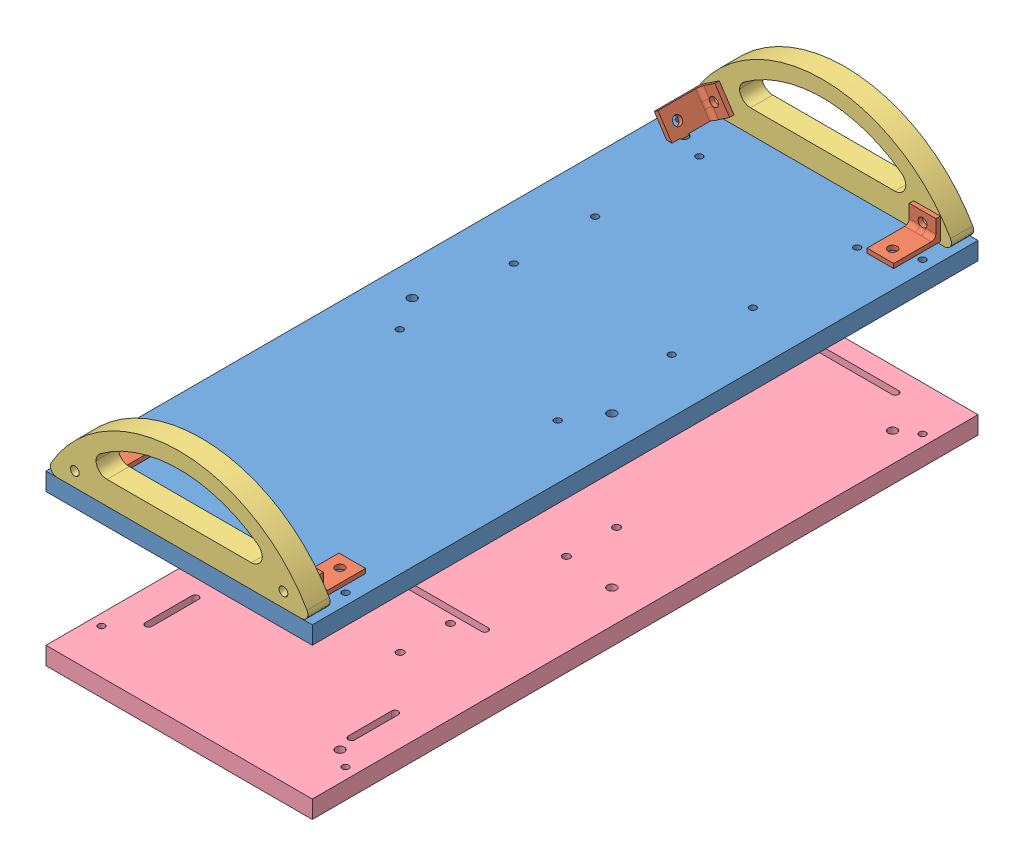
SolidWorks assembly e TRAY ASSEMBLY, configuration Default. Lengths in mm.
Overall size (150 150 300).
8 component instances, 4 part files, 16 mates.
Components (placement in the parent):
- E tray lower-1: E tray lower [Default] at (-39.2466 76 -235.5889) x (0 0 1) z (1 0 0) size (300 8 120)
- l BRACKETT-5: l BRACKETT [Default] at (-24.605 136.2584 -283.17) x (0 1 0) z (0 0 1) size (10 12 21)
- l BRACKETT-6: l BRACKETT [Default] at (-36.605 136.2584 -16.83) x (0 1 0) z (0 0 -1) size (10 12 21)
- l BRACKETT-7: l BRACKETT [Default] at (-76.5282 107.2908 -283.17) x (0.832473 0.554065 0) z (0 0 1) size (10 12 21)
- l BRACKETT-8: l BRACKETT [Default] at (-130.605 136.2584 -16.83) x (0 1 0) z (0 0 -1) size (10 12 21)
- E TRAY SUPPORT-2: E TRAY SUPPORT [Default] at (-77.605 47.3598 -300) x (-1 0 0) z (0 1 0) size (116.08 10 37.84)
- E TRAY SUPPORT-3: E TRAY SUPPORT [Default] at (-77.605 47.3598 -10) x (-1 0 0) z (0 1 0) size (116.08 10 37.84)
- E tray upper-1: E tray upper [Default] at (-52.9013 8 -233.0125) x (0 0 1) z (1 0 0) size (300 8 120)
Mates (geometry in assembly coordinates):
- Coincident14: coincident: line of E tray lower-1 through (-137.605 76 -300) axis (1 0 0); line of E TRAY SUPPORT-2 through (-22.5664 76 -300) axis (-1 0 0)
- Coincident15: coincident: plane of E tray lower-1 through (-39.2466 76 -235.5889) normal (0 1 0); plane of E TRAY SUPPORT-2 through (-17.605 76 -290) normal (0 -1 0)
- Coincident18: coincident: circle of l BRACKETT-7; circle of E TRAY SUPPORT-2
- Coincident19: coincident: circle of l BRACKETT-5; circle of E TRAY SUPPORT-2
- Concentric11: concentric: circle of E tray lower-1; circle of l BRACKETT-5
- Coincident22: coincident: line of E tray lower-1 through (-137.605 76 0) axis (1 0 0); line of E TRAY SUPPORT-3 through (-22.5664 76 0) axis (-1 0 0)
- Coincident23: coincident: plane of E tray lower-1 through (-39.2466 76 -235.5889) normal (0 1 0); plane of E TRAY SUPPORT-3 through (-17.605 76 0) normal (0 -1 0)
- Coincident24: coincident: circle of l BRACKETT-8; circle of E TRAY SUPPORT-3
- Coincident25: coincident: circle of l BRACKETT-6; circle of E TRAY SUPPORT-3
- Concentric12: concentric: circle of E tray lower-1; circle of l BRACKETT-6
- Concentric13: concentric: circle of E tray lower-1; circle of l BRACKETT-8
- Concentric16: concentric: circle of E tray lower-1; circle of E tray upper-1
- Concentric17: concentric: circle of E tray lower-1; circle of E tray upper-1
- Distance1: distance = 60 mm: plane of E tray lower-1 through (-39.2466 68 -235.5889) normal (0 -1 0); plane of E tray upper-1 through (-52.9013 8 -233.0125) normal (0 1 0)
- Coincident35: coincident: plane of E TRAY SUPPORT-3 through (-77.605 47.3598 0) normal (0 0 1); plane of assembly through (0 0 0) normal (0 0 1)
- Coincident36: coincident: plane of E tray upper-1 through (-52.9013 0 -233.0125) normal (0 -1 0); plane of assembly through (0 0 0) normal (0 1 0)
